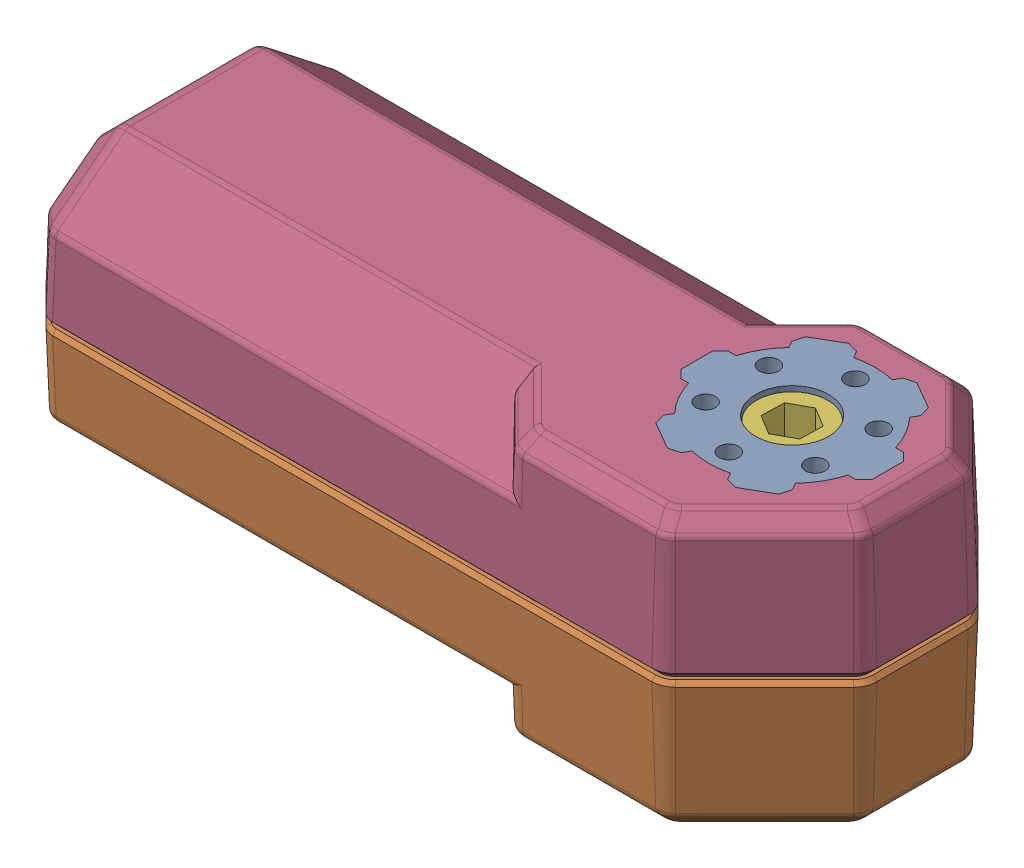
SolidWorks assembly Core Hex, configuration Valor predeterminado. Lengths in mm.
Overall size (96.91 34.63 37.63).
6 component instances, 6 part files, 0 mates.
Components (placement in the parent):
- M04.01.06.17.REV-41-1300-1: M04.01.06.17.REV-41-1300 [Valor predeterminado] at (35.2461 -0.8086 -1.8103) size (24.12 5.7 24)
- M04.01.06.18.REV-41-1300-0.step-1: M04.01.06.18.REV-41-1300-0.step [Valor predeterminado] at (35.2461 -0.8086 -1.8103) size (95.73 17.04 36.49)
- M04.01.06.19.REV-41-1300-1-1: M04.01.06.19.REV-41-1300-1 [Valor predeterminado] at (35.2461 -0.8086 -1.8103) size (1.57 27.85 23.5)
- M04.01.06.20.REV-41-1300-2-1: M04.01.06.20.REV-41-1300-2 [Valor predeterminado] at (35.2461 -0.8086 -1.8103) size (95.73 18.36 36.49)
- M04.01.06.21.REV-41-1300-3-1: M04.01.06.21.REV-41-1300-3 [Valor predeterminado] at (35.2461 -0.8086 -1.8103) size (24 5.7 24.12)
- M04.01.06.22.REV-41-1300-4-1: M04.01.06.22.REV-41-1300-4 [Valor predeterminado] at (35.2461 -0.8086 -1.8103) x (0.950115 0 -0.311898) z (0.311898 0 0.950115) size (27.99 34 27.97)
